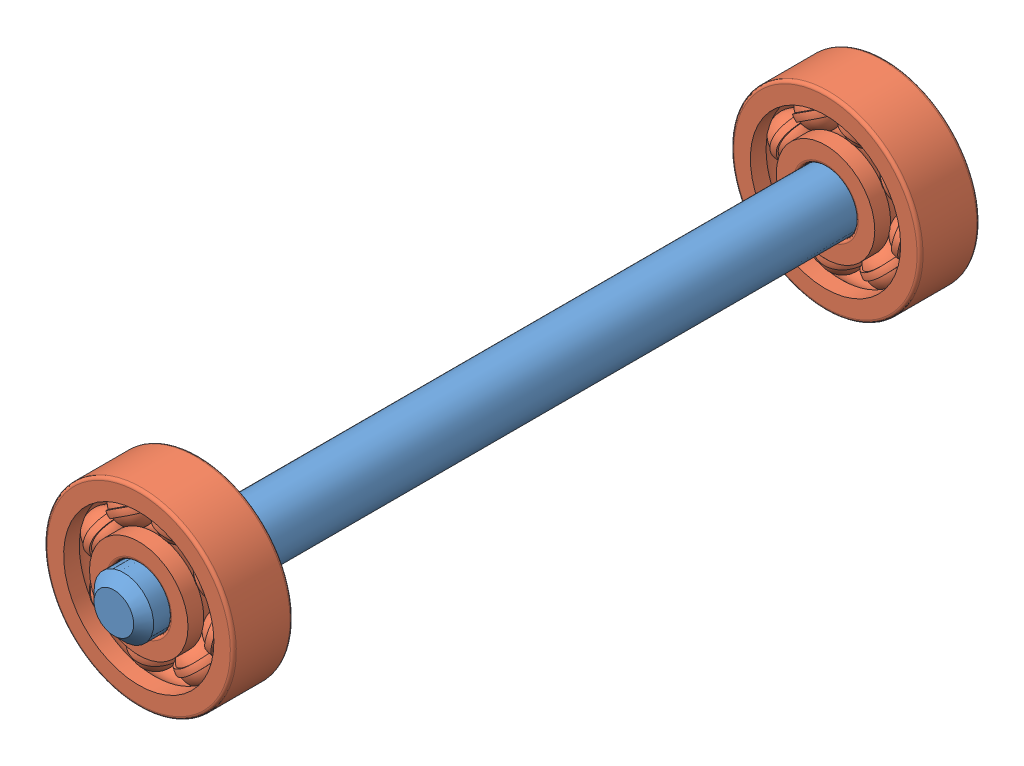
SolidWorks assembly Shaft base-arm1, configuration Domyślna. Lengths in mm.
Overall size (26.31 26.31 105.4).
3 component instances, 2 part files, 5 mates.
Components (placement in the parent):
- Shaft 6x80-1: Shaft 6x80 [Domyślna] at (-24.5738 299.6145 0) x (-0.994675 -0.103065 0) z (0 0 1) size (6 6 105.4)
- Bearing ISO 1224 - 020619 - R,8,DE,AC,8_68-3: Bearing ISO 1224 - 020619 - R,8,DE,AC,8_68 [ISO 1224 - 020619 - R,8,DE,AC,8_68] at (-24.5738 299.6145 -34.5) x (0 0 1) z (0.548835 -0.835931 0) size (6 19 19)
- Bearing ISO 1224 - 020619 - R,8,DE,AC,8_68-4: Bearing ISO 1224 - 020619 - R,8,DE,AC,8_68 [ISO 1224 - 020619 - R,8,DE,AC,8_68] at (-24.5738 299.6145 34.5) x (0 0 1) z (0.548835 -0.835931 0) size (6 19 19)
Mates (geometry in assembly coordinates):
- Koncentryczne17: concentric anti-aligned: cylinder of ? through (-12.5 308.5 33.9907) axis (0 0 1) radius 4; cylinder of Shaft 6x80-1 through (-12.5 308.5 38.9907) axis (0 0 -1) radius 4
- Koncentryczne18: concentric anti-aligned: cylinder of Shaft 6x80-1 through (-24.5738 299.6145 40) axis (0 0 -1) radius 3; cylinder of Bearing ISO 1224 - 020619 - R,8,DE,AC,8_68-3 through (-24.5738 299.6145 -55.1375) axis (0 0 1) radius 3
- Koncentryczne19: concentric anti-aligned: cylinder of Shaft 6x80-1 through (-24.5738 299.6145 40) axis (0 0 -1) radius 3; cylinder of Bearing ISO 1224 - 020619 - R,8,DE,AC,8_68-4 through (-24.5738 299.6145 13.8625) axis (0 0 1) radius 3
- Odległość1: distance = 75 mm anti-aligned: plane of Bearing ISO 1224 - 020619 - R,8,DE,AC,8_68-3 through (-30.8851 295.4708 -37.5) normal (0 0 -1); plane of Bearing ISO 1224 - 020619 - R,8,DE,AC,8_68-4 through (-32.2643 294.5652 37.5) normal (0 0 1)
- Symetrycznie1: symmetric aligned: plane of Bearing ISO 1224 - 020619 - R,8,DE,AC,8_68-3 through (-30.8851 295.4708 -37.5) normal (0 0 -1); plane of Bearing ISO 1224 - 020619 - R,8,DE,AC,8_68-4 through (-32.2643 294.5652 37.5) normal (0 0 1); plane of assembly through (0 0 0) normal (0 0 1)
